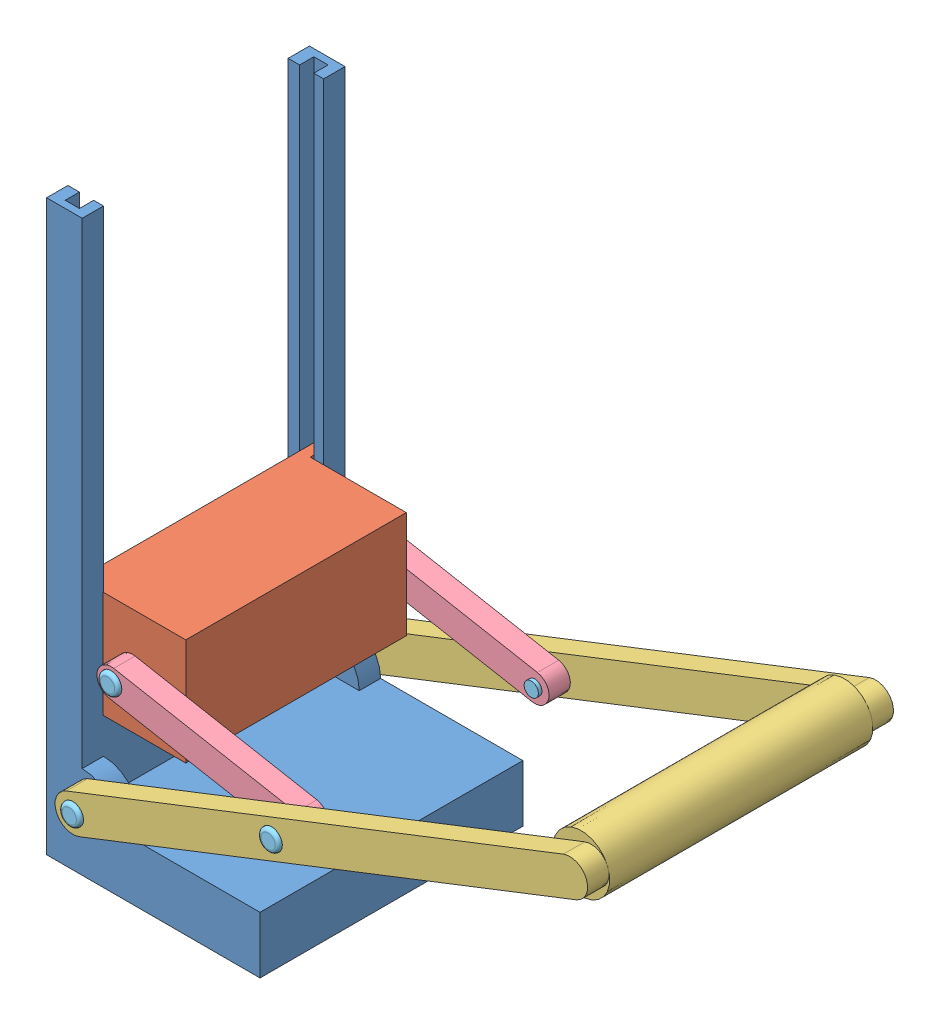
SolidWorks assembly Assem1, configuration Default. Lengths in mm.
Overall size (803.94 800 440).
11 component instances, 5 part files, 28 mates.
Components (placement in the parent):
- Part1_holder-1: Part1_holder [Default] at (112.6352 275.72 331.001) size (300 800 369.52)
- Part1_crusher-1: Part1_crusher [Default] at (158.769 130.72 331.2435) size (150 150 350)
- Part1_handle-1: Part1_handle [Default] at (559.3191 110.7365 116.2435) x (-0.931677 -0.363287 0) z (0 0 1) size (800.06 80 430)
- Part1_shorLink-1: Part1_shorLink [Default] at (361.6061 107.105 146.2435) x (0.983363 -0.181654 0) z (0 0 1) size (300 40 30)
- Part1_shorLink-2: Part1_shorLink [Default] at (361.6061 107.105 486.2435) x (0.983363 -0.181654 0) z (0 0 1) size (300 40 30)
- Part1_bolt-1: Part1_bolt [Default] at (233.769 130.72 141.2435) size (30 30 70)
- Part1_bolt-2: Part1_bolt [Default] at (489.4433 83.49 111.2435) size (30 30 70)
- Part1_bolt-3: Part1_bolt [Default] at (209.94 -25.496 111.2435) size (30 30 70)
- Part1_bolt-4: Part1_bolt [Default] at (209.94 -25.496 551.2435) x (-0.904633 -0.426192 0) z (0 0 -1) size (30 30 70)
- Part1_bolt-5: Part1_bolt [Default] at (489.4433 83.49 551.2435) x (-0.904633 -0.426192 0) z (0 0 -1) size (30 30 70)
- Part1_bolt-6: Part1_bolt [Default] at (233.769 130.72 521.2435) x (-0.904633 -0.426192 0) z (0 0 -1) size (30 30 70)
Mates (geometry in assembly coordinates):
- Coincident1: coincident anti-aligned: plane of Part1_holder-1 through (112.6352 275.72 156.2435) normal (0 0 1); plane of Part1_crusher-1 through (158.769 130.72 156.2435) normal (0 0 -1)
- Parallel1: parallel anti-aligned: plane of Part1_holder-1 through (112.6352 275.72 505.7585) normal (0 0 -1); plane of Part1_crusher-1 through (158.769 130.72 506.2435) normal (0 0 1)
- Coincident3: coincident anti-aligned: plane of Part1_holder-1 through (158.769 675.72 156.2435) normal (1 0 0); plane of Part1_crusher-1 through (158.769 130.72 331.2435) normal (-1 0 0)
- Coincident4: coincident anti-aligned: plane of Part1_holder-1 through (192.6352 675.72 146.2435) normal (0 0 -1); plane of Part1_handle-1 through (559.3191 110.7365 146.2435) normal (0 0 1)
- Concentric1: concentric anti-aligned: cylinder of Part1_holder-1 through (209.94 -25.496 515.7585) axis (0 0 -1) radius 10; cylinder of Part1_handle-1 through (209.94 -25.496 116.2435) axis (0 0 1) radius 10
- Concentric2: concentric anti-aligned: cylinder of Part1_holder-1 through (209.94 -25.496 515.7585) axis (0 0 -1) radius 10; cylinder of Part1_handle-1 through (209.94 -25.496 116.2435) axis (0 0 1) radius 10
- Parallel2: parallel anti-aligned: plane of Part1_holder-1 through (192.6352 675.72 515.7585) normal (0 0 1); plane of Part1_handle-1 through (559.3191 110.7365 516.2435) normal (0 0 -1)
- Concentric3: concentric anti-aligned: cylinder of Part1_crusher-1 through (233.769 130.72 241.2435) axis (0 0 -1) radius 10; cylinder of Part1_shorLink-1 through (233.769 130.72 146.2435) axis (0 0 1) radius 10
- Coincident6: coincident anti-aligned: plane of Part1_crusher-1 through (308.769 205.72 176.2435) normal (0 0 -1); plane of Part1_shorLink-1 through (361.6061 107.105 176.2435) normal (0 0 1)
- Concentric4: concentric aligned: cylinder of Part1_handle-1 through (489.4433 83.49 116.2435) axis (0 0 1) radius 10; cylinder of Part1_shorLink-1 through (489.4433 83.49 146.2435) axis (0 0 1) radius 10
- Coincident7: coincident anti-aligned: plane of Part1_handle-1 through (559.3191 110.7365 146.2435) normal (0 0 1); plane of Part1_shorLink-1 through (361.6061 107.105 146.2435) normal (0 0 -1)
- Concentric5: concentric aligned: cylinder of Part1_handle-1 through (489.4433 83.49 116.2435) axis (0 0 1) radius 10; cylinder of Part1_shorLink-2 through (489.4433 83.49 486.2435) axis (0 0 1) radius 10
- Concentric7: concentric aligned: cylinder of Part1_crusher-1 through (233.769 130.72 421.2435) axis (0 0 1) radius 10; cylinder of Part1_shorLink-2 through (233.769 130.72 486.2435) axis (0 0 1) radius 10
- Coincident9: coincident anti-aligned: plane of Part1_handle-1 through (559.3191 110.7365 516.2435) normal (0 0 -1); plane of Part1_shorLink-2 through (361.6061 107.105 516.2435) normal (0 0 1)
- Coincident10: coincident anti-aligned: plane of Part1_crusher-1 through (308.769 205.72 486.2435) normal (0 0 1); plane of Part1_shorLink-2 through (361.6061 107.105 486.2435) normal (0 0 -1)
- Concentric8: concentric anti-aligned: cylinder of Part1_handle-1 through (489.4433 83.49 116.2435) axis (0 0 1) radius 10; cylinder of Part1_bolt-2 through (489.4433 83.49 181.2435) axis (0 0 -1) radius 10
- Coincident11: coincident anti-aligned: plane of Part1_handle-1 through (559.3191 110.7365 116.2435) normal (0 0 -1); plane of Part1_bolt-2 through (489.4433 83.49 116.2435) normal (0 0 1)
- Concentric9: concentric anti-aligned: cylinder of Part1_shorLink-1 through (233.769 130.72 146.2435) axis (0 0 1) radius 10; cylinder of Part1_bolt-1 through (233.769 130.72 211.2435) axis (0 0 -1) radius 10
- Coincident12: coincident anti-aligned: plane of Part1_shorLink-1 through (361.6061 107.105 146.2435) normal (0 0 -1); plane of Part1_bolt-1 through (233.769 130.72 146.2435) normal (0 0 1)
- Concentric10: concentric anti-aligned: cylinder of Part1_handle-1 through (209.94 -25.496 116.2435) axis (0 0 1) radius 10; cylinder of Part1_bolt-3 through (209.94 -25.496 181.2435) axis (0 0 -1) radius 10
- Coincident13: coincident anti-aligned: plane of Part1_handle-1 through (559.3191 110.7365 116.2435) normal (0 0 -1); plane of Part1_bolt-3 through (209.94 -25.496 116.2435) normal (0 0 1)
- Concentric11: concentric aligned: cylinder of Part1_handle-1 through (209.94 -25.496 116.2435) axis (0 0 1) radius 10; cylinder of Part1_bolt-4 through (209.94 -25.496 481.2435) axis (0 0 1) radius 10
- Coincident14: coincident anti-aligned: plane of Part1_handle-1 through (559.3191 110.7365 546.2435) normal (0 0 1); plane of Part1_bolt-4 through (209.94 -25.496 546.2435) normal (0 0 -1)
- Concentric12: concentric aligned: cylinder of Part1_handle-1 through (489.4433 83.49 116.2435) axis (0 0 1) radius 10; cylinder of Part1_bolt-5 through (489.4433 83.49 481.2435) axis (0 0 1) radius 10
- Coincident15: coincident anti-aligned: plane of Part1_handle-1 through (559.3191 110.7365 546.2435) normal (0 0 1); plane of Part1_bolt-5 through (489.4433 83.49 546.2435) normal (0 0 -1)
- Concentric13: concentric aligned: cylinder of Part1_shorLink-2 through (233.769 130.72 486.2435) axis (0 0 1) radius 10; cylinder of Part1_bolt-6 through (233.769 130.72 451.2435) axis (0 0 1) radius 10
- Coincident16: coincident anti-aligned: plane of Part1_shorLink-2 through (361.6061 107.105 516.2435) normal (0 0 1); plane of Part1_bolt-6 through (233.769 130.72 516.2435) normal (0 0 -1)
- LimitDistance1: limit distance = 100 mm anti-aligned: plane of Part1_crusher-1 through (308.769 55.72 486.2435) normal (0 -1 0); plane of Part1_holder-1 through (442.6352 -44.28 515.7585) normal (0 1 0)
